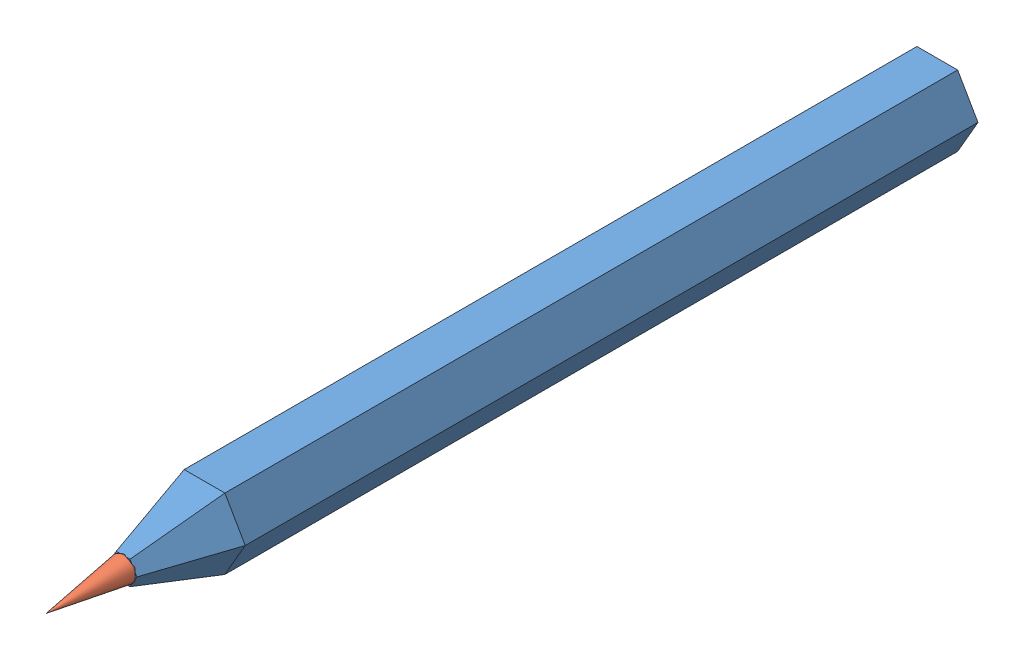
SolidWorks assembly Sestava tužka, configuration Výchozí. Lengths in mm.
Overall size (10 8.66 109.47).
2 component instances, 2 part files, 2 mates.
Components (placement in the parent):
- dřevo-1: dřevo [Výchozí] at (-1.0928 0.7589 -50) size (10 8.66 100)
- tuha-1: tuha [Výchozí] at (-1.0928 0.7589 50) x (-0.510086 0.860124 0) z (0 0 -1) size (3 3 109.47)
Mates (geometry in assembly coordinates):
- Soustředná3: concentric: cylinder of dřevo-1; cylinder of tuha-1
- Sjednocená1: coincident aligned: plane of dřevo-1; plane of tuha-1
